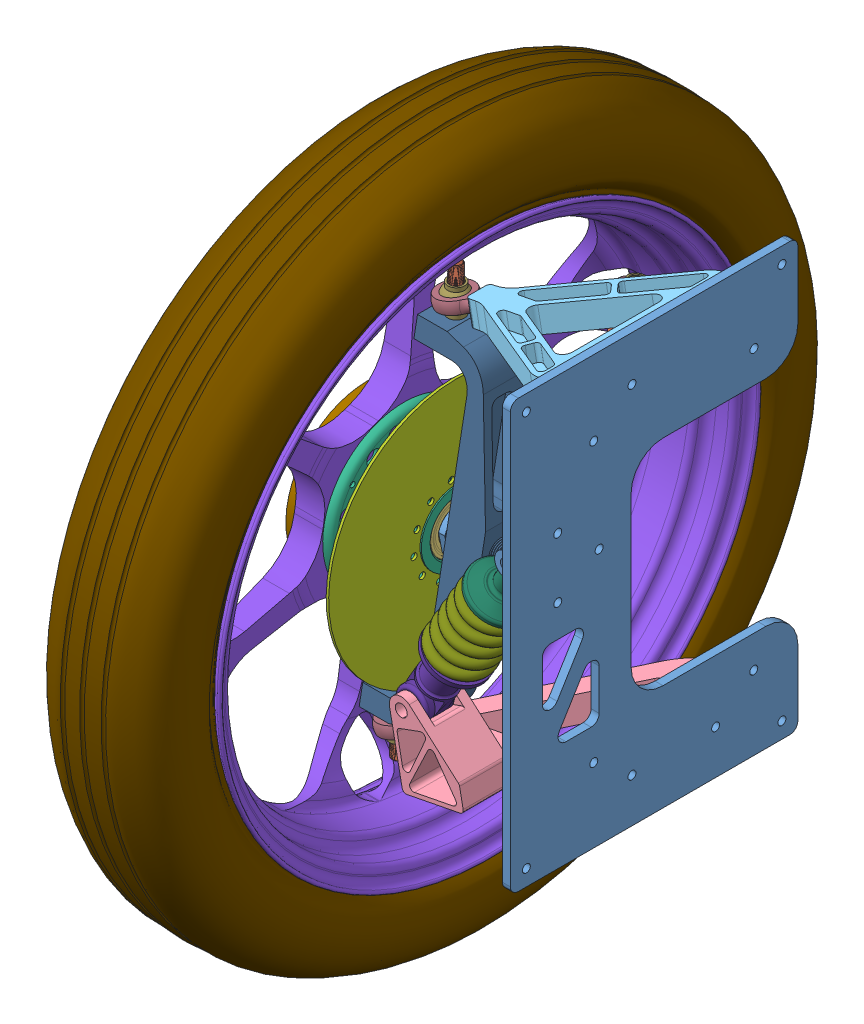
SolidWorks assembly NewShockWheeland Suspension, configuration Default. Lengths in mm.
Overall size (271.85 732.15 732.15).
27 component instances, 21 part files, 54 mates.
Components (placement in the parent):
- Spindle_Light-1: Spindle_Light [Default] at (77.608 100.5934 168.4727) x (-1 0 0) z (0 0.195874 -0.980629) size (132.55 34 30)
- SKF_6003-2Z.stp-1: SKF_6003-2Z.stp [Default] at (24.108 100.5934 168.4727) x (-1 0 0) z (0 0.824074 -0.566482) size (10 35 35)
- SKF_6004-2Z.stp-1: SKF_6004-2Z.stp [Default] at (70.608 100.5934 168.4727) x (-1 0 0) z (0 0.99144 -0.13056) size (12 42 42)
- NewWishbone-1: NewWishbone [Default] at (67.6994 -39.6364 201.1983) x (0 0 -1) z (0.981395 0.192 0) size (183.89 64.96 127)
- NewWishboneTop-1: NewWishboneTop [Default] at (67.6994 229.4429 191.6779) x (0 0 -1) z (0.981395 0.192 0) size (146.05 19.05 127)
- Hub-1: Hub [Default] at (47.1911 100.5934 168.4727) x (0 -0.59032 -0.807169) z (0 -0.807169 0.59032) size (129.24 86.35 129.24)
- BasicBrakeDisc-1: BasicBrakeDisc [Default] at (68.608 100.5934 168.4727) x (0 0.919293 -0.393575) z (1 0 0) size (203.2 203.2 2)
- rimmachined16-1: rimmachined16 [Default] at (51.1 100.5934 168.4727) x (-1 0 0) z (0 -0.766952 0.641705) size (163.94 431.57 431.57)
- Nut-1: Nut [Default] at (-17.5866 100.5934 168.4727) x (0 -0.714783 -0.699347) z (1 0 0) size (130 130 16.12)
- FrontSpindle-1: FrontSpindle [Default] at (77.608 100.5934 168.4727) x (0 0 -1) z (1 0 0) size (78.71 246.85 73.5)
- 91257A659_Zinc Yellow-Chromate Plated Hex Head Screw-1: 91257A659_Zinc Yellow-Chromate Plated Hex Head Screw [91257A659] at (47.175 231.0056 145.2721) x (0 1 0) z (-0.369814 0 -0.929106) size (57.6 16.5 14.29)
- 91257A659_Zinc Yellow-Chromate Plated Hex Head Screw-2: 91257A659_Zinc Yellow-Chromate Plated Hex Head Screw [91257A659] at (47.175 -29.8187 191.6733) x (0 -1 0) z (0.631563 0 -0.775325) size (57.6 16.5 14.29)
- Super-Swivel Ball Joint Ball End2-3: Super-Swivel Ball Joint Ball End2 [6960T231] at (28.1399 235.1331 144.5197) x (-0.039495 0 0.99922) z (0 1 0) size (20.64 20.64 22.23)
- Super-Swivel Ball Joint Ball End2-5: Super-Swivel Ball Joint Ball End2 [6960T231] at (47.175 -33.9462 172.6233) x (1 0 0) z (0 -1 0) size (20.64 20.64 22.23)
- Swivel Ball Joint Rod End-4: Swivel Ball Joint Rod End [6960T231] at (65.8706 238.7907 145.2721) x (0 0 -1) z (-0.192 0.981395 0) size (28.57 68.26 9.89)
- Swivel Ball Joint Rod End-7: Swivel Ball Joint Rod End [6960T231] at (65.8706 -30.2886 191.6733) x (0 0 1) z (0.192 -0.981395 0) size (28.57 68.26 9.89)
- shock assembly-3: shock assembly [Default] at (124.3458 68.0957 220.2483) x (0 0 -1) z (-0.861378 0.507965 0) size (46 186.78 47.49)
  - Shock Absorber Rod_1-1: Shock Absorber Rod_1 [Default] at (0 -64.2216 0) x (0.958984 0 0.283461) z (-0.283461 0 0.958984) size (6.35 19.21 6.35)
  - Shock Anchor_1-1: Shock Anchor_1 [Default] at (0 -111.8466 0) x (1 0 0) z (0 0 -1) size (46 57.15 46)
  - Shock Spring_1-1: Shock Spring_1 [Default] at (0 -64.2216 0) size (46 72.22 47.49)
  - Shock Tube 1_1-1: Shock Tube 1_1 [Default] at (0 33.655 0) size (46 110.41 46)
- Michelin Tire-1: Michelin Tire [Default] at (51.1 100.5934 168.4727) x (1 0 0) z (0 0.397996 -0.917387) size (101.13 556.61 556.61)
- FrontSuspensionMountingPlate-1: FrontSuspensionMountingPlate [Default] at (203.3849 297.0258 29.7529) x (0 0 1) z (-1 0 0) size (228.6 339.73 31.75)
- Standoff-1: Standoff [Default] at (82.7521 89.5336 59.2858) x (1 0 0) z (0 0.184735 0.982788) size (25.4 101.6 25.4)
- Super-Swivel Ball Joint Ball End2-6: Super-Swivel Ball Joint Ball End2 [6960T231] at (68.3425 198.0043 26.2178) x (0.654099 -0.139735 -0.74339) z (0 -0.982788 0.184735) size (20.64 20.64 22.23)
- Swivel Ball Joint Rod End-6: Swivel Ball Joint Rod End [6960T231] at (101.4236 197.5767 35.8508) x (-0.159574 -0.158819 -0.974327) z (0.117814 0.976856 -0.178527) size (28.57 68.26 9.89)
- SteeringArmMount3-1: SteeringArmMount3 [Default] at (77.608 98.936 152.6312) x (-1 0 0) z (0 -0.184735 -0.982788) size (32.44 66.16 106.1)
Mates (geometry in assembly coordinates):
- Concentric1: concentric aligned: cylinder of Spindle_Light-1 through (-2.892 100.5934 168.4727) axis (-1 0 0) radius 8.5; cylinder of SKF_6003-2Z.stp-1 through (-25.892 100.5934 168.4727) axis (-1 0 0) radius 8.5
- Coincident1: coincident aligned: plane of Spindle_Light-1 through (14.108 108.9288 170.1376) normal (-1 0 0); plane of SKF_6003-2Z.stp-1 through (14.108 105.5785 175.7245) normal (-1 0 0)
- Concentric3: concentric aligned: cylinder of Spindle_Light-1 through (-2.892 100.5934 168.4727) axis (-1 0 0) radius 10; cylinder of SKF_6004-2Z.stp-1 through (20.608 100.5934 168.4727) axis (-1 0 0) radius 10
- Coincident2: coincident anti-aligned: plane of Spindle_Light-1 through (70.608 112.361 170.8232) normal (-1 0 0); plane of SKF_6004-2Z.stp-1 through (70.608 102.3534 181.8373) normal (1 0 0)
- Concentric4: concentric anti-aligned: cylinder of SKF_6004-2Z.stp-1 through (20.608 100.5934 168.4727) axis (-1 0 0) radius 21; cylinder of Hub-1 through (973.2188 100.5934 168.4727) axis (1 0 0) radius 21
- Coincident3: coincident anti-aligned: plane of SKF_6004-2Z.stp-1 through (58.608 103.0212 186.9085) normal (-1 0 0); plane of Hub-1 through (58.608 89.3773 153.1365) normal (1 0 0)
- Concentric6: concentric anti-aligned: cylinder of Hub-1 through (973.2188 100.5934 168.4727) axis (1 0 0) radius 29; cylinder of BasicBrakeDisc-1 through (70.608 100.5934 168.4727) axis (-1 0 0) radius 28.956
- Coincident5: coincident anti-aligned: plane of Hub-1 through (68.608 83.4741 145.0648) normal (1 0 0); plane of BasicBrakeDisc-1 through (68.608 100.5934 168.4727) normal (-1 0 0)
- Concentric7: concentric anti-aligned: cylinder of Hub-1 through (973.2188 100.5934 168.4727) axis (1 0 0) radius 47; cylinder of rimmachined16-1 through (56 100.5934 168.4727) axis (-1 0 0) radius 47
- Coincident6: coincident anti-aligned: plane of Hub-1 through (28.8 72.8484 130.5357) normal (-1 0 0); plane of rimmachined16-1 through (28.8 74.9252 137.7946) normal (1 0 0)
- Concentric8: concentric aligned: circle of Hub-1; circle of Nut-1
- Coincident9: coincident anti-aligned: plane of rimmachined16-1 through (6 100.5934 168.4727) normal (-1 0 0); plane of Nut-1 through (6 74.5039 142.9465) normal (1 0 0)
- Coincident10: coincident anti-aligned: plane of Nut-1 through (0 54.1325 123.0152) normal (-1 0 0)
- Coincident11: coincident anti-aligned: circle of Spindle_Light-1; circle of FrontSpindle-1
- Concentric9: concentric aligned: cylinder of FrontSpindle-1 through (47.175 194.0206 145.2721) axis (0 1 0) radius 4.7625; cylinder of 91257A659_Zinc Yellow-Chromate Plated Hex Head Screw-1 through (47.175 208.7806 145.2721) axis (0 1 0) radius 4.7625
- Coincident12: coincident anti-aligned: plane of FrontSpindle-1 through (32.608 208.7806 168.4727) normal (0 -1 0); plane of 91257A659_Zinc Yellow-Chromate Plated Hex Head Screw-1 through (48.3652 208.7806 137.1095) normal (0 1 0)
- Concentric10: concentric aligned: cylinder of FrontSpindle-1 through (47.175 7.1663 191.6733) axis (0 -1 0) radius 4.7625; cylinder of 91257A659_Zinc Yellow-Chromate Plated Hex Head Screw-2 through (47.175 -7.5937 191.6733) axis (0 -1 0) radius 4.7625
- Coincident13: coincident anti-aligned: plane of FrontSpindle-1 through (32.608 -7.5937 168.4727) normal (0 1 0); plane of 91257A659_Zinc Yellow-Chromate Plated Hex Head Screw-2 through (48.4889 -7.5937 183.5297) normal (0 -1 0)
- Coincident17: coincident anti-aligned: plane of FrontSpindle-1 through (106.108 224.0206 129.1191) normal (0 1 0); plane of Super-Swivel Ball Joint Ball End2-3 through (47.175 224.0206 145.2721) normal (0 -1 0)
- Concentric17: concentric aligned: cylinder of 91257A659_Zinc Yellow-Chromate Plated Hex Head Screw-1 through (47.175 208.7806 145.2721) axis (0 1 0) radius 4.7625; cylinder of Super-Swivel Ball Joint Ball End2-3 through (47.175 224.8143 145.2721) axis (0 1 0) radius 4.7625
- Concentric18: concentric aligned: cylinder of 91257A659_Zinc Yellow-Chromate Plated Hex Head Screw-2 through (47.175 -7.5937 191.6733) axis (0 -1 0) radius 4.7625; cylinder of Super-Swivel Ball Joint Ball End2-5 through (47.175 -23.6275 191.6733) axis (0 -1 0) radius 4.7625
- Coincident18: coincident anti-aligned: plane of FrontSpindle-1 through (106.108 -22.8337 207.8263) normal (0 -1 0); plane of Super-Swivel Ball Joint Ball End2-5 through (47.175 -22.8337 191.6733) normal (0 1 0)
- Concentric19: concentric: sphere of Super-Swivel Ball Joint Ball End2-3; sphere of Swivel Ball Joint Rod End-4
- LimitAngle3: limit planar angle = 0.1932 rad anti-aligned: plane of Swivel Ball Joint Rod End-4 through (34.0296 227.9107 159.5596) normal (0.192 -0.981395 0); plane of 91257A659_Zinc Yellow-Chromate Plated Hex Head Screw-1 through (47.175 259.5806 145.2721) normal (0 1 0)
- Concentric20: concentric: sphere of Super-Swivel Ball Joint Ball End2-5; sphere of MirrorSwivel Ball Joint Rod End-1
- LimitAngle4: limit planar angle = 0.1932 rad: plane of MirrorSwivel Ball Joint Rod End-1 through (32.277 -32.2103 177.3858) normal (-0.192 0.981395 0); plane of Super-Swivel Ball Joint Ball End2-5 through (47.175 -45.0587 191.6733) normal (0 -1 0)
- Concentric21: concentric aligned: cylinder of NewWishboneTop-1 through (103.2617 246.1059 145.2721) axis (-0.981395 -0.192 0) radius 4.7625; cylinder of Swivel Ball Joint Rod End-4 through (65.8706 238.7907 145.2721) axis (-0.981395 -0.192 0) radius 4.7625
- Coincident20: coincident aligned: plane of NewWishboneTop-1 through (64.0418 248.1384 191.6779) normal (-0.981395 -0.192 0); circle of Swivel Ball Joint Rod End-4
- Parallel7: parallel aligned: plane of NewWishboneTop-1 through (64.0418 248.1384 191.6779) normal (-0.192 0.981395 0); plane of Swivel Ball Joint Rod End-4 through (32.277 236.869 159.5596) normal (-0.192 0.981395 0)
- Concentric22: concentric: circle of NewWishbone-1; circle of MirrorSwivel Ball Joint Rod End-1
- Coincident22: coincident: plane of NewWishbone-1 through (64.0418 -20.9408 201.1983) normal (-0.981395 -0.192 0); circle of MirrorSwivel Ball Joint Rod End-1
- Parallel13: parallel aligned: plane of NewWishbone-1 through (64.0418 -20.9408 201.1983) normal (-0.192 0.981395 0); plane of NewWishboneTop-1 through (64.0418 248.1384 191.6779) normal (-0.192 0.981395 0)
- Concentric28: concentric anti-aligned: cylinder of NewWishbone-1 through (97.5736 22.6968 239.2983) axis (0 0 -1) radius 4.7625; cylinder of shock assembly-3/Shock Tube 1_1-1 through (97.5736 22.6968 208.1833) axis (0 0 1) radius 4.9166
- Coincident36: coincident anti-aligned: plane of NewWishbone-1 through (67.6994 -39.6364 232.3133) normal (0 0 -1); plane of shock assembly-3/Shock Tube 1_1-1 through (97.5736 22.6968 232.3133) normal (0 0 1)
- Parallel26: parallel: plane of NewWishbone-1 through (64.0418 -20.9408 201.1983) normal (-0.192 0.981395 0); plane of MirrorSwivel Ball Joint Rod End-1 through (32.277 -32.2103 177.3858) normal (-0.192 0.981395 0)
- Parallel27: parallel: plane of NewWishbone-1 through (64.0418 -20.9408 201.1983) normal (-0.192 0.981395 0); plane of MirrorSwivel Ball Joint Rod End-1 through (32.277 -32.2103 177.3858) normal (-0.192 0.981395 0)
- Parallel28: parallel aligned: plane of NewWishbone-1 through (64.0418 -20.9408 182.1483) normal (0 0 -1); plane of NewWishboneTop-1 through (64.0418 248.1384 182.1529) normal (0 0 -1)
- Concentric29: concentric anti-aligned: cylinder of rimmachined16-1 through (136.6092 100.5934 168.4727) axis (1 0 0) radius 192.7898; cylinder of Michelin Tire-1 through (-51.6229 100.5934 168.4727) axis (-1 0 0) radius 203
- Concentric30: concentric aligned: cylinder of NewWishboneTop-1 through (181.1599 261.3458 201.2029) axis (0 0 -1) radius 4.7625; cylinder of FrontSuspensionMountingPlate-1 through (181.1599 261.3458 258.3529) axis (0 0 -1) radius 4.7625
- Coincident38: coincident anti-aligned: plane of NewWishboneTop-1 through (64.0418 248.1384 55.1529) normal (0 0 -1); plane of FrontSuspensionMountingPlate-1 through (171.6349 297.0258 55.1529) normal (0 0 1)
- Concentric31: concentric anti-aligned: cylinder of shock assembly-3/Shock Anchor_1-1 through (181.1599 164.4378 213.8983) axis (0 0 1) radius 5; cylinder of FrontSuspensionMountingPlate-1 through (181.1599 164.4378 258.3529) axis (0 0 -1) radius 4.7625
- Coincident50: coincident anti-aligned: plane of FrontSpindle-1 through (106.108 -22.8337 175.5203) normal (0 -0.184735 -0.982788); plane of SteeringArmMount2-1 through (77.608 98.936 152.6312) normal (0 0.184735 0.982788)
- Coincident51: coincident anti-aligned: line of FrontSpindle-1 through (106.108 80.5637 156.0846) axis (0 0.982788 -0.184735); line of SteeringArmMount2-1 through (106.108 120.6231 148.5547) axis (0 -0.982788 0.184735)
- Coincident52: coincident: point of FrontSpindle-1; point of SteeringArmMount2-1
- Coincident53: coincident aligned: circle of SteeringArmMount2-1; circle of Standoff-1
- Concentric32: concentric aligned: circle of Standoff-1; circle of Super-Swivel Ball Joint Ball End2-6
- Coincident54: coincident anti-aligned: plane of Standoff-1 through (82.7521 189.3849 40.5168) normal (0 0.982788 -0.184735); circle of Super-Swivel Ball Joint Ball End2-6
- Concentric33: concentric: sphere of Super-Swivel Ball Joint Ball End2-6; sphere of Swivel Ball Joint Rod End-6
- Coincident55: coincident anti-aligned: plane of FrontSpindle-1 through (106.108 -22.8337 175.5203) normal (0 -0.184735 -0.982788); plane of SteeringArmMount3-1 through (77.608 98.936 152.6312) normal (0 0.184735 0.982788)
- Coincident56: coincident anti-aligned: line of FrontSpindle-1 through (106.108 80.5637 156.0846) axis (0 0.982788 -0.184735); line of SteeringArmMount3-1 through (106.108 120.6231 148.5547) axis (0 -0.982788 0.184735)
- Coincident57: coincident: point of FrontSpindle-1; point of SteeringArmMount3-1
- Concentric34: concentric anti-aligned: cylinder of Standoff-1 through (82.7521 189.3849 40.5168) axis (0 -0.982788 0.184735) radius 4.7625; cylinder of SteeringArmMount3-1 through (82.7521 52.0894 66.3242) axis (0 0.982788 -0.184735) radius 4.7625
- Distance1: distance = 0 mm anti-aligned: plane of Standoff-1 through (82.7521 89.5336 59.2858) normal (0 -0.982788 0.184735); plane of SteeringArmMount3-1 through (73.6709 106.8018 151.1527) normal (0 0.982788 -0.184735)
- Coincident58: coincident anti-aligned: plane of rimmachined16-1 through (51.1 100.5934 168.4727) normal (-1 0 0); plane of Michelin Tire-1 through (51.1 100.5934 168.4727) normal (1 0 0)
